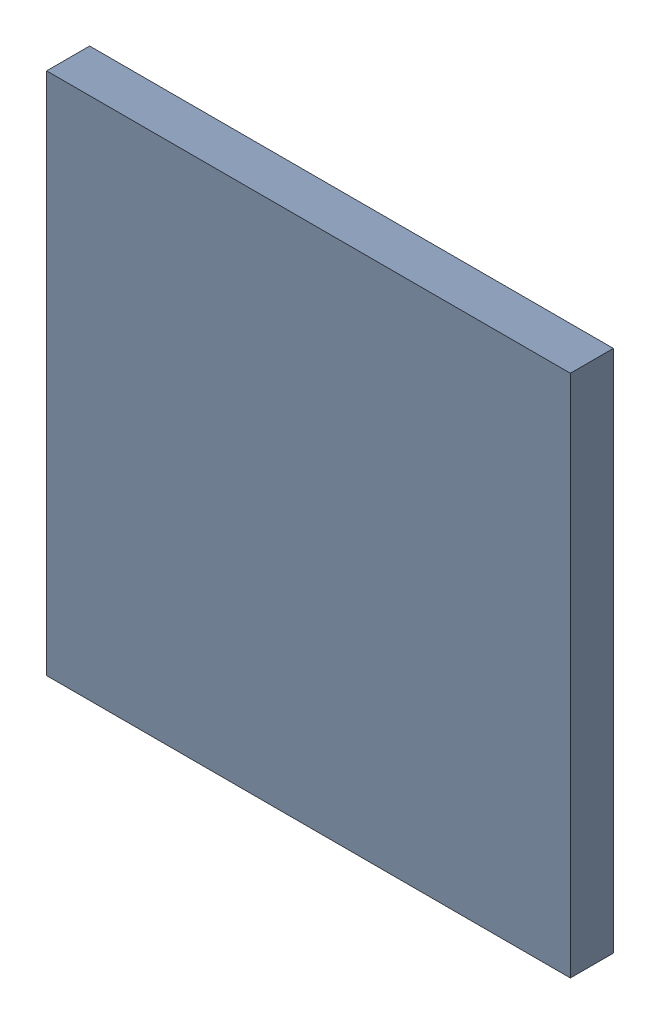
SolidWorks assembly U5Kanaloa_v2.0.0_Power, configuration Default. Lengths in mm.
Overall size (14 14 1.15).
2 component instances, 1 part files, 0 mates.
Components (placement in the parent):
- 378153408-1: 378153408 [Default] at (88.9 101.6 0.05) size (14 14 1.15)
  - Extruded_24-1: Extruded_24 [Default] at origin size (14 14 1.15)
